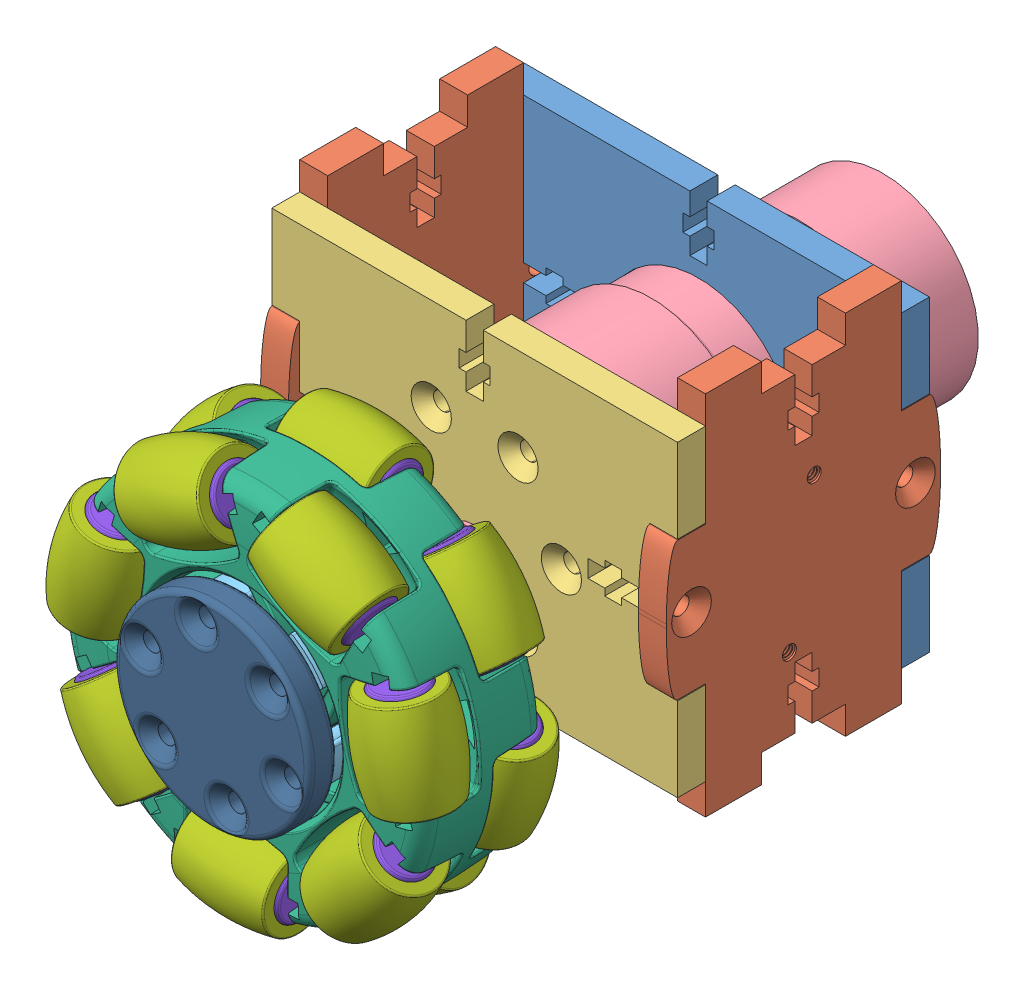
SolidWorks assembly Wheel_module_fix_tapp_v2, configuration Défaut. Lengths in mm.
Overall size (96.72 96.72 123.68).
65 component instances, 10 part files, 18 mates.
Components (placement in the parent):
- Motor_mount_back__fix_tapp_v2-1: Motor_mount_back__fix_tapp_v2 [Défaut] at (-11.1957 -6.6974 85.083) x (-1 0 0) z (0 -1 0) size (72.5 5 55)
- Wheelmodule_Middle_fix_tapp_v2-1: Wheelmodule_Middle_fix_tapp_v2 [Défaut] at (25.0543 -6.6974 102.583) x (0 0 -1) z (0 -1 0) size (49.12 5.24 65.5)
- Wheelmodule_Middle_fix_tapp_v2-2: Wheelmodule_Middle_fix_tapp_v2 [Défaut] at (-47.4457 -6.6974 102.583) x (0 0 1) z (0 -1 0) size (49.12 5.24 65.5)
- Motor_mount_front_fix_tapp_v2-1: Motor_mount_front_fix_tapp_v2 [Défaut] at (-11.1957 -9.1974 120.083) size (72.5 55 5)
- BDSG-37-40-R150_motor-1: BDSG-37-40-R150_motor [Défaut] at (-11.1957 -9.1974 120.083) x (-1 0 0) z (0 0 1) size (37 37 89)
- moyeux_print-1: moyeux_print [Défaut] at (-11.1957 -16.1974 144.583) size (31 32.5 36.51)
- 2_75_Omni-Directional_Wheel-2: 2_75_Omni-Directional_Wheel [Défaut] at (-11.1957 -16.1974 155.833) x (0.912946 0.408081 0) z (0 0 -1) size (80.5 79.46 40.46)
  - 276-1902-002 Rev3-1: 276-1902-002 Rev3 [Défaut] at origin size (67.01 66.02 22.52)
  - 276-1902-010 Rev1-1: 276-1902-010 Rev1 [Défaut] at (0 27.5 8) x (1 0 0) z (0 0.828233 0.560383) size (23 18.05 18.05)
    - 276-1902-011 Rev1-1: 276-1902-011 Rev1 [Défaut] at (0 -6.325 -26.7627) x (1 0 0) z (0 -0.973191 0.23) size (16.5 15 15)
    - 276-1902-012 Rev1-1: 276-1902-012 Rev1 [Défaut] at origin size (17.51 10.2 10.2)
    - 276-1902-003 Rev1-1: 276-1902-003 Rev1 [Défaut] x (0 -0.928523 0.371275) z (1 0 0) size (2 2 23)
  - 276-1902-010 Rev1-2: 276-1902-010 Rev1 [Défaut] at (0 -27.5 -8) x (1 0 0) z (0 0.410464 0.911877) size (23 18.05 18.05)
    - 276-1902-011 Rev1-1: 276-1902-011 Rev1 [Défaut] at (0 -6.325 -26.7627) x (1 0 0) z (0 -0.973191 0.23) size (16.5 15 15)
    - 276-1902-012 Rev1-1: 276-1902-012 Rev1 [Défaut] at origin size (17.51 10.2 10.2)
    - 276-1902-003 Rev1-1: 276-1902-003 Rev1 [Défaut] x (0 -0.928523 0.371275) z (1 0 0) size (2 2 23)
  - 276-1902-010 Rev1-3: 276-1902-010 Rev1 [Défaut] at (-21.5004 -17.146 -8) x (0.62349 -0.781831 0) z (0.320913 0.25592 0.911877) size (23 18.05 18.05)
    - 276-1902-011 Rev1-1: 276-1902-011 Rev1 [Défaut] at (0 -6.325 -26.7627) x (1 0 0) z (0 -0.973191 0.23) size (16.5 15 15)
    - 276-1902-012 Rev1-1: 276-1902-012 Rev1 [Défaut] at origin size (17.51 10.2 10.2)
    - 276-1902-003 Rev1-1: 276-1902-003 Rev1 [Défaut] x (0 -0.928523 0.371275) z (1 0 0) size (2 2 23)
  - 276-1902-010 Rev1-4: 276-1902-010 Rev1 [Défaut] at (-26.8105 6.1193 -8) x (-0.222521 -0.974928 0) z (0.400172 -0.091337 0.911877) size (23 18.05 18.05)
    - 276-1902-011 Rev1-1: 276-1902-011 Rev1 [Défaut] at (0 -6.325 -26.7627) x (1 0 0) z (0 -0.973191 0.23) size (16.5 15 15)
    - 276-1902-012 Rev1-1: 276-1902-012 Rev1 [Défaut] at origin size (17.51 10.2 10.2)
    - 276-1902-003 Rev1-1: 276-1902-003 Rev1 [Défaut] x (0 -0.928523 0.371275) z (1 0 0) size (2 2 23)
  - 276-1902-010 Rev1-5: 276-1902-010 Rev1 [Défaut] at (-11.9318 24.7766 -8) x (-0.900969 -0.433884 0) z (0.178093 -0.369815 0.911877) size (23 18.05 18.05)
    - 276-1902-011 Rev1-1: 276-1902-011 Rev1 [Défaut] at (0 -6.325 -26.7627) x (1 0 0) z (0 -0.973191 0.23) size (16.5 15 15)
    - 276-1902-012 Rev1-1: 276-1902-012 Rev1 [Défaut] at origin size (17.51 10.2 10.2)
    - 276-1902-003 Rev1-1: 276-1902-003 Rev1 [Défaut] x (0 -0.928523 0.371275) z (1 0 0) size (2 2 23)
  - 276-1902-010 Rev1-6: 276-1902-010 Rev1 [Défaut] at (11.9318 24.7766 -8) x (-0.900969 0.433884 0) z (-0.178093 -0.369815 0.911877) size (23 18.05 18.05)
    - 276-1902-011 Rev1-1: 276-1902-011 Rev1 [Défaut] at (0 -6.325 -26.7627) x (1 0 0) z (0 -0.973191 0.23) size (16.5 15 15)
    - 276-1902-012 Rev1-1: 276-1902-012 Rev1 [Défaut] at origin size (17.51 10.2 10.2)
    - 276-1902-003 Rev1-1: 276-1902-003 Rev1 [Défaut] x (0 -0.928523 0.371275) z (1 0 0) size (2 2 23)
  - 276-1902-010 Rev1-7: 276-1902-010 Rev1 [Défaut] at (26.8105 6.1193 -8) x (-0.222521 0.974928 0) z (-0.400172 -0.091337 0.911877) size (23 18.05 18.05)
    - 276-1902-011 Rev1-1: 276-1902-011 Rev1 [Défaut] at (0 -6.325 -26.7627) x (1 0 0) z (0 -0.973191 0.23) size (16.5 15 15)
    - 276-1902-012 Rev1-1: 276-1902-012 Rev1 [Défaut] at origin size (17.51 10.2 10.2)
    - 276-1902-003 Rev1-1: 276-1902-003 Rev1 [Défaut] x (0 -0.928523 0.371275) z (1 0 0) size (2 2 23)
  - 276-1902-010 Rev1-8: 276-1902-010 Rev1 [Défaut] at (21.5004 -17.146 -8) x (0.62349 0.781831 0) z (-0.320913 0.25592 0.911877) size (23 18.05 18.05)
    - 276-1902-011 Rev1-1: 276-1902-011 Rev1 [Défaut] at (0 -6.325 -26.7627) x (1 0 0) z (0 -0.973191 0.23) size (16.5 15 15)
    - 276-1902-012 Rev1-1: 276-1902-012 Rev1 [Défaut] at origin size (17.51 10.2 10.2)
    - 276-1902-003 Rev1-1: 276-1902-003 Rev1 [Défaut] x (0 -0.928523 0.371275) z (1 0 0) size (2 2 23)
  - 276-1902-010 Rev1-9: 276-1902-010 Rev1 [Défaut] at (21.5004 17.146 8) x (0.62349 -0.781831 0) z (0.647539 0.516395 0.560383) size (23 18.05 18.05)
    - 276-1902-011 Rev1-1: 276-1902-011 Rev1 [Défaut] at (0 -6.325 -26.7627) x (1 0 0) z (0 -0.973191 0.23) size (16.5 15 15)
    - 276-1902-012 Rev1-1: 276-1902-012 Rev1 [Défaut] at origin size (17.51 10.2 10.2)
    - 276-1902-003 Rev1-1: 276-1902-003 Rev1 [Défaut] x (0 -0.928523 0.371275) z (1 0 0) size (2 2 23)
  - 276-1902-010 Rev1-10: 276-1902-010 Rev1 [Défaut] at (26.8105 -6.1193 8) x (-0.222521 -0.974928 0) z (0.807468 -0.184299 0.560383) size (23 18.05 18.05)
    - 276-1902-011 Rev1-1: 276-1902-011 Rev1 [Défaut] at (0 -6.325 -26.7627) x (1 0 0) z (0 -0.973191 0.23) size (16.5 15 15)
    - 276-1902-012 Rev1-1: 276-1902-012 Rev1 [Défaut] at origin size (17.51 10.2 10.2)
    - 276-1902-003 Rev1-1: 276-1902-003 Rev1 [Défaut] x (0 -0.928523 0.371275) z (1 0 0) size (2 2 23)
  - 276-1902-010 Rev1-11: 276-1902-010 Rev1 [Défaut] at (11.9318 -24.7766 8) x (-0.900969 -0.433884 0) z (0.359357 -0.746212 0.560383) size (23 18.05 18.05)
    - 276-1902-011 Rev1-1: 276-1902-011 Rev1 [Défaut] at (0 -6.325 -26.7627) x (1 0 0) z (0 -0.973191 0.23) size (16.5 15 15)
    - 276-1902-012 Rev1-1: 276-1902-012 Rev1 [Défaut] at origin size (17.51 10.2 10.2)
    - 276-1902-003 Rev1-1: 276-1902-003 Rev1 [Défaut] x (0 -0.928523 0.371275) z (1 0 0) size (2 2 23)
  - 276-1902-010 Rev1-12: 276-1902-010 Rev1 [Défaut] at (-11.9318 -24.7766 8) x (-0.900969 0.433884 0) z (-0.359357 -0.746212 0.560383) size (23 18.05 18.05)
    - 276-1902-011 Rev1-1: 276-1902-011 Rev1 [Défaut] at (0 -6.325 -26.7627) x (1 0 0) z (0 -0.973191 0.23) size (16.5 15 15)
    - 276-1902-012 Rev1-1: 276-1902-012 Rev1 [Défaut] at origin size (17.51 10.2 10.2)
    - 276-1902-003 Rev1-1: 276-1902-003 Rev1 [Défaut] x (0 -0.928523 0.371275) z (1 0 0) size (2 2 23)
  - 276-1902-010 Rev1-13: 276-1902-010 Rev1 [Défaut] at (-26.8105 -6.1193 8) x (-0.222521 0.974928 0) z (-0.807468 -0.184299 0.560383) size (23 18.05 18.05)
    - 276-1902-011 Rev1-1: 276-1902-011 Rev1 [Défaut] at (0 -6.325 -26.7627) x (1 0 0) z (0 -0.973191 0.23) size (16.5 15 15)
    - 276-1902-012 Rev1-1: 276-1902-012 Rev1 [Défaut] at origin size (17.51 10.2 10.2)
    - 276-1902-003 Rev1-1: 276-1902-003 Rev1 [Défaut] x (0 -0.928523 0.371275) z (1 0 0) size (2 2 23)
  - 276-1902-010 Rev1-14: 276-1902-010 Rev1 [Défaut] at (-21.5004 17.146 8) x (0.62349 0.781831 0) z (-0.647539 0.516395 0.560383) size (23 18.05 18.05)
    - 276-1902-011 Rev1-1: 276-1902-011 Rev1 [Défaut] at (0 -6.325 -26.7627) x (1 0 0) z (0 -0.973191 0.23) size (16.5 15 15)
    - 276-1902-012 Rev1-1: 276-1902-012 Rev1 [Défaut] at origin size (17.51 10.2 10.2)
    - 276-1902-003 Rev1-1: 276-1902-003 Rev1 [Défaut] x (0 -0.928523 0.371275) z (1 0 0) size (2 2 23)
- moyeux_print_2-1: moyeux_print_2 [Défaut] at (-11.1957 -16.1974 167.083) size (35 35 5.36)
Mates (geometry in assembly coordinates):
- Coïncidente1: coincident anti-aligned: plane of Motor_mount_back__fix_tapp_v2-1 through (20.0543 -6.6974 85.083) normal (1 0 0); plane of Wheelmodule_Middle_fix_tapp_v2-1 through (20.0543 -19.6474 85.083) normal (-1 0 0)
- Coïncidente2: coincident aligned: plane of Motor_mount_back__fix_tapp_v2-1 through (-42.4457 20.8026 85.083) normal (0 1 0); plane of Wheelmodule_Middle_fix_tapp_v2-1 through (20.0543 20.8026 85.083) normal (0 1 0)
- Coïncidente6: coincident anti-aligned: plane of Motor_mount_back__fix_tapp_v2-1 through (-11.1957 -6.6974 85.083) normal (0 0 1); plane of Wheelmodule_Middle_fix_tapp_v2-2 through (-47.4457 6.8526 85.083) normal (0 0 -1)
- Coïncidente7: coincident aligned: plane of Wheelmodule_Middle_fix_tapp_v2-1 through (20.0543 20.8026 85.083) normal (0 1 0); plane of Motor_mount_front_fix_tapp_v2-1 through (-6.1993 20.8026 125.083) normal (0 1 0)
- Coïncidente8: coincident aligned: plane of Wheelmodule_Middle_fix_tapp_v2-1 through (25.0543 -19.6474 85.083) normal (1 0 0); plane of Motor_mount_front_fix_tapp_v2-1 through (25.0543 -9.1974 120.083) normal (1 0 0)
- Coïncidente9: coincident anti-aligned: plane of Wheelmodule_Middle_fix_tapp_v2-1 through (25.0543 6.8526 120.083) normal (0 0 1); plane of Motor_mount_front_fix_tapp_v2-1 through (-11.1957 -9.1974 120.083) normal (0 0 -1)
- Coaxiale1: concentric anti-aligned: cylinder of Motor_mount_front_fix_tapp_v2-1 through (-11.1957 -16.1974 125.083) axis (0 0 1) radius 6.1; cylinder of BDSG-37-40-R150_motor-1 through (-11.1957 -16.1974 126.083) axis (0 0 -1) radius 6
- Coïncidente10: coincident anti-aligned: plane of Motor_mount_front_fix_tapp_v2-1 through (-11.1957 -9.1974 120.083) normal (0 0 -1); plane of BDSG-37-40-R150_motor-1 through (-11.1957 -9.1974 120.083) normal (0 0 1)
- Coaxiale2: concentric aligned: cylinder of Motor_mount_front_fix_tapp_v2-1 through (-18.9457 4.226 125.083) axis (0 0 1) radius 1.6; cylinder of BDSG-37-40-R150_motor-1 through (-18.9457 4.226 120.083) axis (0 0 1) radius 1.25
- Coaxiale3: concentric aligned: cylinder of BDSG-37-40-R150_motor-1 through (-11.1957 -16.1974 141.083) axis (0 0 -1) radius 3; cylinder of moyeux_print-1 through (-11.1957 -16.1974 165.583) axis (0 0 -1) radius 3.5
- Parallèle1: parallel anti-aligned: plane of BDSG-37-40-R150_motor-1 through (-9.5374 -18.6974 129.083) normal (0 -1 0); plane of moyeux_print-1 through (-11.1957 -18.8974 165.583) normal (0 1 0)
- Distance1: distance = 3.5 mm: plane of moyeux_print-1 through (-11.1957 -16.1974 144.583) normal (0 0 1); plane of BDSG-37-40-R150_motor-1 through (-11.1957 -16.1974 141.083) normal (0 0 1)
- Coaxiale4: concentric anti-aligned: cylinder of BDSG-37-40-R150_motor-1 through (-11.1957 -16.1974 141.083) axis (0 0 -1) radius 3; circle of 2_75_Omni-Directional_Wheel-2/276-1902-002 Rev3-1
- Coïncidente13: coincident: plane of moyeux_print-1 through (-11.1957 -16.1974 144.583) normal (0 0 1); plane of 2_75_Omni-Directional_Wheel-2/276-1902-002 Rev3-1 through (-11.1957 -16.1974 144.583) normal (0 0 -1)
- Verrouiller1: lock: unknown of BDSG-37-40-R150_motor-1; unknown of 2_75_Omni-Directional_Wheel-2/276-1902-002 Rev3-1
- Coïncidente14: coincident anti-aligned: plane of 2_75_Omni-Directional_Wheel-2/276-1902-002 Rev3-1 through (-11.1957 -16.1974 167.083) normal (0 0 1); plane of moyeux_print_2-1 through (-11.1957 -16.1974 167.083) normal (0 0 -1)
- Coaxiale5: concentric aligned: cylinder of moyeux_print-1 through (-23.7969 -11.9822 165.583) axis (0 0 -1) radius 1.4; cylinder of moyeux_print_2-1 through (-23.7969 -11.9822 172.083) axis (0 0 -1) radius 1.6
- Coaxiale6: concentric aligned: cylinder of moyeux_print-1 through (1.4055 -20.4125 165.583) axis (0 0 -1) radius 1.4; cylinder of moyeux_print_2-1 through (1.4055 -20.4125 172.083) axis (0 0 -1) radius 1.6
